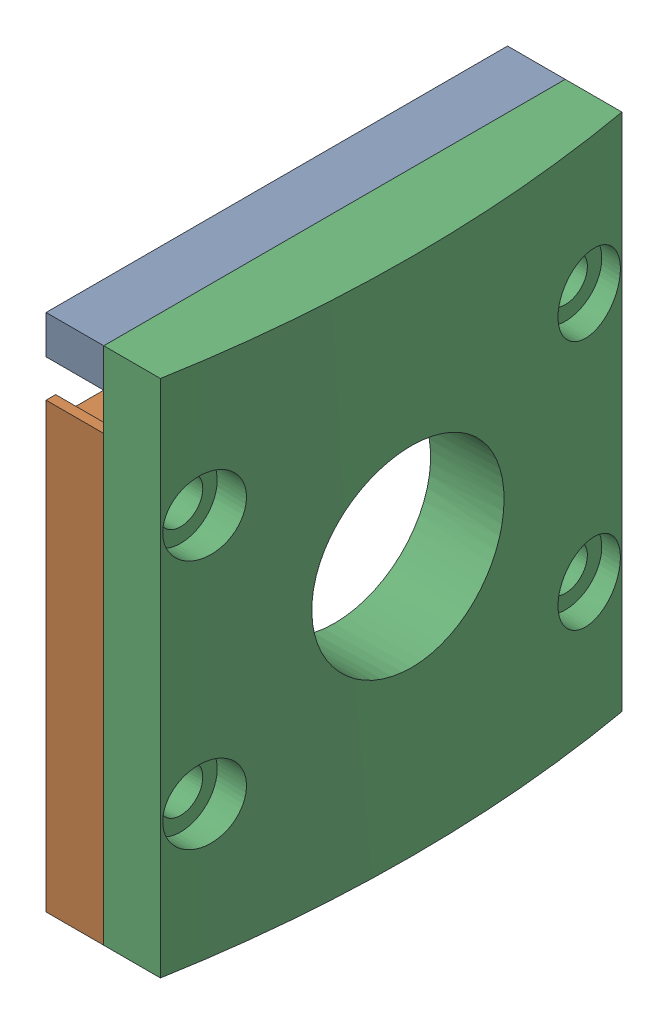
SolidWorks assembly drawerCapAss, configuration Default. Lengths in mm.
Overall size (7 27 24).
2 component instances, 2 part files, 3 mates.
Components (placement in the parent):
- BottleDrawerGearLockContainerLayer-1: BottleDrawerGearLockContainerLayer [Default] at (658.4953 864.1474 1274.0867) x (0 0 1) z (-1 0 0) size (24 27 3)
- Bottle Draw Cap-1: Bottle Draw Cap [Default] at (655.4953 864.1474 1274.0867) x (0 0 -1) z (0 1 0) size (24 4 27)
Mates (geometry in assembly coordinates):
- Coincident4: coincident: plane of BottleDrawerGearLockContainerLayer-1 through (658.4953 864.1474 1274.0867) normal (1 0 0); plane of Bottle Draw Cap-1 through (658.4953 864.1474 1274.0867) normal (-1 0 0)
- Concentric2: concentric: circle of BottleDrawerGearLockContainerLayer-1; circle of Bottle Draw Cap-1
- Coincident6: coincident aligned: plane of BottleDrawerGearLockContainerLayer-1 through (655.4953 850.6474 1262.0867) normal (0 -1 0); plane of Bottle Draw Cap-1 through (652.4953 850.6474 1286.0867) normal (0 -1 0)
